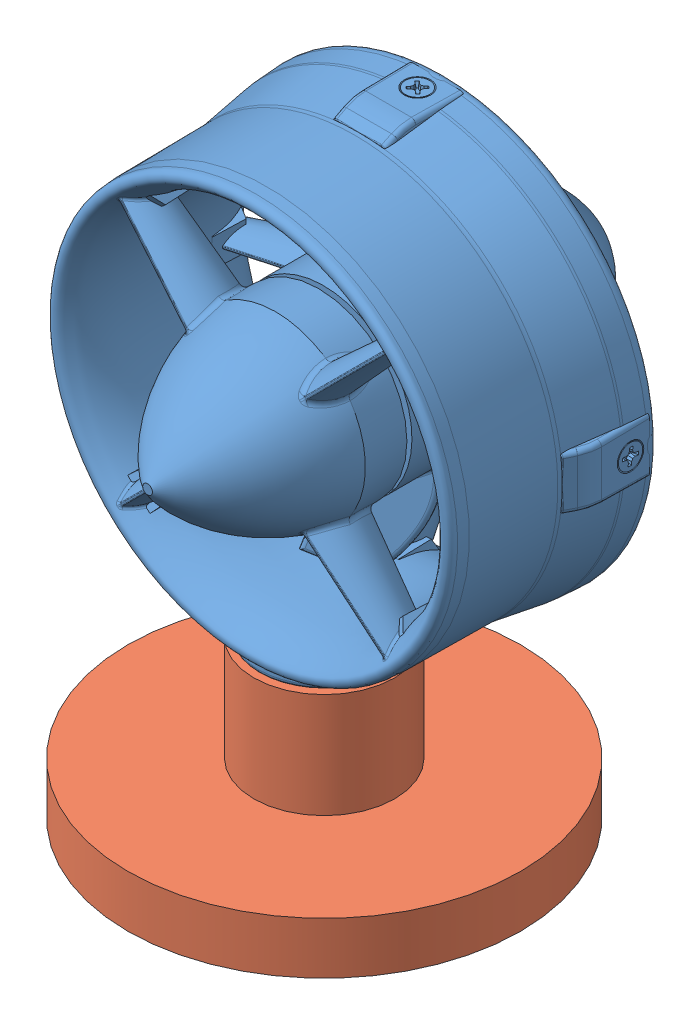
SolidWorks assembly thruster_assem, configuration Default. Lengths in mm.
Overall size (96.71 132.85 105.33).
2 component instances, 2 part files, 4 mates.
Components (placement in the parent):
- T100-ASM-CW-THRUSTER-R1-1: T100-ASM-CW-THRUSTER-R1 [Default] at (15.8959 45.8047 93.5384) size (96.71 97.51 100.86)
- thruster_bracket-1: thruster_bracket [Default] at (15.8959 -3.1953 93.5384) x (-1 0 0) z (0 -1 0) size (89 89 35.5)
Mates (geometry in assembly coordinates):
- InPlace2: in place: plane of T100-ASM-CW-THRUSTER-R1-1 through (15.8959 -3.1953 98.7902) normal (0 -1 0); plane of ? through (0 -3.1953 0) normal (0 -1 0); moOrthogonalPlaneRef_w of T100-ASM-CW-THRUSTER-R1-1 through (15.8959 -3.1953 98.7902) normal (0 -1 0); plane of ? through (0 -3.1953 0) normal (0 0 -1); plane of T100-ASM-CW-THRUSTER-R1-1 through (15.8959 -3.1953 98.7902) normal (0 -1 0); plane of ? through (0 -3.1953 0) normal (-1 0 0); plane of T100-ASM-CW-THRUSTER-R1-1 through (15.8959 -3.1953 98.7902) normal (0 -1 0); unknown of thruster_bracket-1
- Coincident4: coincident aligned: plane of T100-ASM-CW-THRUSTER-R1-1; plane of thruster_bracket-1
- Coincident5: coincident aligned: moOrthogonalPlaneRef_w of T100-ASM-CW-THRUSTER-R1-1 through (15.8959 -3.1953 93.5384) normal (0 0 -1); plane of thruster_bracket-1 through (15.8959 -3.1953 93.5384) normal (0 0 -1)
- Coincident6: coincident anti-aligned: moOrthogonalPlaneRef_w of T100-ASM-CW-THRUSTER-R1-1 through (15.8959 -3.1953 93.5384) normal (1 0 0); plane of thruster_bracket-1 through (15.8959 -3.1953 93.5384) normal (-1 0 0)
